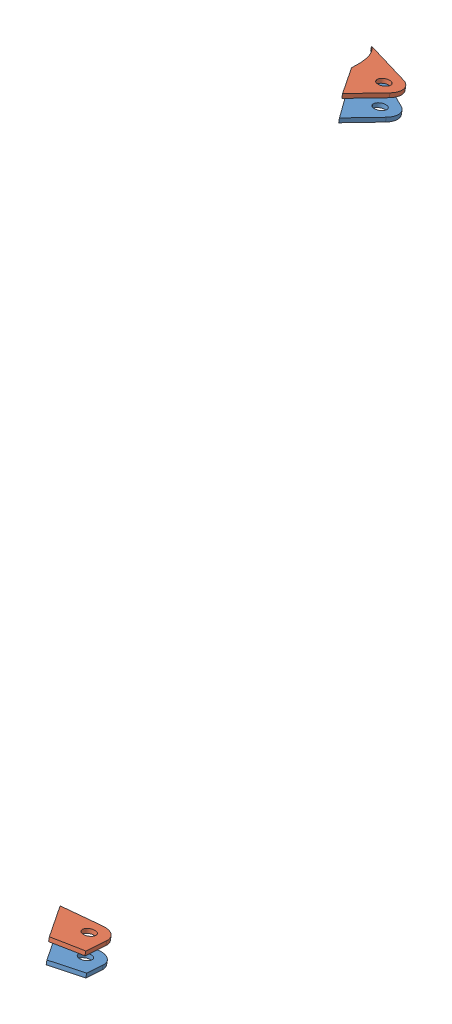
SolidWorks assembly Left sidePUTM-F-FR-MT-Aero-RW-Mountings, configuration Domyślna. Lengths in mm.
Overall size (440.97 126.76 591.66).
3 component instances, 3 part files, 0 mates.
Components (placement in the parent):
- PUTM-F-FR-MT-Aero-RW-Inside-Kinematics-1: PUTM-F-FR-MT-Aero-RW-Inside-Kinematics [Domyślna] at (0 365.9457 -71.1326) x (1 0 0) z (0 -0.981627 0.190809)
- Left sidePUTM-F-FR-MT-Aero-RW-Inside-Mounting-1: Left sidePUTM-F-FR-MT-Aero-RW-Inside-Mounting [Domyślna] at origin size (432.93 116.74 590.82)
- Left sidePUTM-F-FR-MT-Aero-RW-Outside-Mounting-1: Left sidePUTM-F-FR-MT-Aero-RW-Outside-Mounting [Domyślna] at origin size (440.97 116.74 590.82)
